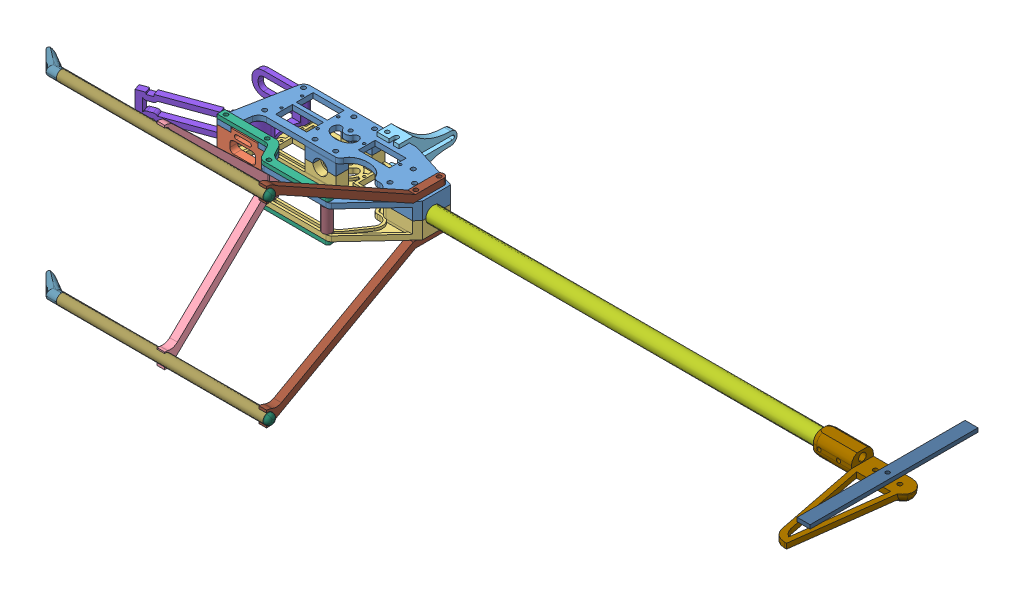
SolidWorks assembly helicopter_v5_assembly, configuration По умолчанию. Lengths in mm.
Overall size (563.49 164 196.13).
20 component instances, 15 part files, 49 mates.
Components (placement in the parent):
- frame_v5_half_left-1: frame_v5_half_left [По умолчанию] at (57.718 86.6344 66.9188) size (134.96 13 71.7)
- motor_frame-1: motor_frame [По умолчанию] at (18.368 77.6344 100.9188) x (1 0 0) z (0 -1 0) size (40 6 24)
- frame_v5_half_right-1: frame_v5_half_right [По умолчанию] at (57.718 64.6344 66.9188) size (134.96 13 71.7)
- chassis_v5-1: chassis_v5 [Default] at (45.218 77.6344 120.8231) x (0 -1 0) z (0 0 1) size (164 7 87.2)
- swash_rail-1: swash_rail [По умолчанию] at (83.718 77.5344 52.9188) x (1 0 0) z (0 1 0) size (18.35 45 34.51)
- lower_frame_v5-1: lower_frame_v5 [По умолчанию] at (57.718 90.6344 66.9188) size (99.55 3 19.7)
- lower_frame_v5-2: lower_frame_v5 [По умолчанию] at (57.718 61.6344 66.9188) size (99.55 3 19.7)
- tail_boom-1: tail_boom [Default] at (112.8303 77.6344 74.3035) x (0 0.376859 -0.92627) z (0 -0.92627 -0.376859) size (12 347 12)
- battery_mount-1: battery_mount [Default] at (14.718 86.6344 88.9188) x (-1 0 0) z (0 0 1) size (73.78 18 66.23)
- tail_motor_mount-1: tail_motor_mount [По умолчанию] at (453.8954 79.938 65.8035) x (1 0 0) z (0 -1 0) size (69.62 97.35 16.58)
- tail_prop_model-1: tail_prop_model [Default] at (484.3303 77.1344 74.3035) size (10 3 130)
- chassis_rear_v5-1: chassis_rear_v5 [Default] at (124.718 89.6344 86.1188) x (0 -1 0) z (0 0 1) size (68 6 140.23)
- chassis_rear_v5-2: chassis_rear_v5 [Default] at (130.718 65.6344 86.1188) x (0 1 0) z (0 0 1) size (68 6 140.23)
- carbon_skid-1: carbon_skid [Default] at (-29.282 2.6344 200.2088) x (0 -1 0) z (0 0 1) size (8 160 8)
- carbon_skid-2: carbon_skid [Default] at (130.718 152.6344 200.2088) x (0 1 0) z (0 0 1) size (8 160 8)
- frame_spacer-1: frame_spacer [Default] at (93.718 68.6344 117.6231) size (7 18 7)
- chassis_v3_skid_cap_front-1: chassis_v3_skid_cap_front [По умолчанию] at (-46.4523 148.6344 199.9451) size (31 8 15)
- chassis_v3_skid_cap_front-2: chassis_v3_skid_cap_front [По умолчанию] at (-46.4523 -1.3656 199.9451) size (31 8 15)
- chassis_v3_skid_cap_rear-3: chassis_v3_skid_cap_rear [По умолчанию] at (147.8884 151.3508 204.0065) x (-1 0 0) z (0 -0.924225 -0.381849) size (11.5 8 8)
- chassis_v3_skid_cap_rear-4: chassis_v3_skid_cap_rear [По умолчанию] at (147.8884 1.3508 204.0065) x (-1 0 0) z (0 -0.924225 -0.381849) size (11.5 8 8)
Mates (geometry in assembly coordinates):
- Концентричный1: concentric anti-aligned: cylinder of frame_v5_half_left-1 through (1.718 90.6344 103.9188) axis (0 -1 0) radius 1.7; cylinder of motor_frame-1 through (1.718 65.6344 103.9188) axis (0 1 0) radius 1.6
- Совпадение1: coincident anti-aligned: plane of frame_v5_half_left-1 through (47.9182 86.6344 115.6231) normal (0 -1 0); plane of motor_frame-1 through (8.718 86.6344 106.9188) normal (0 1 0)
- Концентричный2: concentric anti-aligned: cylinder of frame_v5_half_left-1 through (33.718 90.6344 103.9188) axis (0 -1 0) radius 1.7; cylinder of motor_frame-1 through (33.718 65.6344 103.9188) axis (0 1 0) radius 1.6
- Концентричный3: concentric anti-aligned: cylinder of motor_frame-1 through (1.718 65.6344 103.9188) axis (0 1 0) radius 1.6; cylinder of frame_v5_half_right-1 through (1.718 68.6344 103.9188) axis (0 -1 0) radius 1.7
- Концентричный4: concentric anti-aligned: cylinder of motor_frame-1 through (33.718 65.6344 103.9188) axis (0 1 0) radius 1.6; cylinder of frame_v5_half_right-1 through (33.718 68.6344 103.9188) axis (0 -1 0) radius 1.7
- Совпадение2: coincident anti-aligned: plane of motor_frame-1 through (-2.132 68.6344 106.9188) normal (0 -1 0); plane of frame_v5_half_right-1 through (47.9182 68.6344 115.6231) normal (0 1 0)
- Concentric1: concentric anti-aligned: cylinder of frame_v5_half_left-1 through (48.718 90.6344 117.6231) axis (0 -1 0) radius 1.7; cylinder of chassis_v5-1 through (48.718 -4.3656 117.6231) axis (0 1 0) radius 1.75
- Coincident1: coincident anti-aligned: plane of frame_v5_half_left-1 through (47.9182 86.6344 115.6231) normal (0 -1 0); plane of chassis_v5-1 through (52.218 86.6344 113.6231) normal (0 1 0)
- Parallel3: parallel aligned: plane of frame_v5_half_right-1 through (53.4322 68.6344 114.6206) normal (0 0 -1); plane of chassis_v5-1 through (52.218 86.6344 113.6231) normal (0 0 -1)
- Concentric3: concentric anti-aligned: cylinder of frame_v5_half_left-1 through (75.718 90.6344 52.9188) axis (0 -1 0) radius 1.7; cylinder of swash_rail-1 through (75.718 61.5334 52.9188) axis (0 1 0) radius 1.6
- Coincident6: coincident anti-aligned: plane of frame_v5_half_left-1 through (94.3308 90.6344 48.9188) normal (0 0 -1); plane of swash_rail-1 through (83.718 77.5344 48.9188) normal (0 0 1)
- Coincident7: coincident anti-aligned: plane of frame_v5_half_left-1 through (47.9182 90.6344 115.6231) normal (0 1 0); plane of swash_rail-1 through (88.718 90.6344 56.9188) normal (0 -1 0)
- Concentric4: concentric aligned: cylinder of frame_v5_half_left-1 through (1.718 90.6344 103.9188) axis (0 -1 0) radius 1.7; cylinder of lower_frame_v5-1 through (1.718 93.6344 103.9188) axis (0 -1 0) radius 1.6
- Concentric5: concentric aligned: cylinder of frame_v5_half_left-1 through (93.718 90.6344 117.6231) axis (0 -1 0) radius 1.7; cylinder of lower_frame_v5-1 through (93.718 93.6344 117.6231) axis (0 -1 0) radius 1.6
- Coincident8: coincident anti-aligned: plane of frame_v5_half_left-1 through (47.9182 90.6344 115.6231) normal (0 1 0); plane of lower_frame_v5-1 through (47.9182 90.6344 115.6231) normal (0 -1 0)
- Concentric6: concentric aligned: cylinder of frame_v5_half_right-1 through (1.718 68.6344 103.9188) axis (0 -1 0) radius 1.7; cylinder of lower_frame_v5-2 through (1.718 64.6344 103.9188) axis (0 -1 0) radius 1.6
- Concentric7: concentric aligned: cylinder of frame_v5_half_right-1 through (93.718 68.6344 117.6231) axis (0 -1 0) radius 1.7; cylinder of lower_frame_v5-2 through (93.718 64.6344 117.6231) axis (0 -1 0) radius 1.6
- Coincident9: coincident anti-aligned: plane of frame_v5_half_right-1 through (47.9182 64.6344 115.6231) normal (0 -1 0); plane of lower_frame_v5-2 through (47.9182 64.6344 115.6231) normal (0 1 0)
- Concentric8: concentric anti-aligned: cylinder of frame_v5_half_right-1 through (112.8303 77.6344 74.3035) axis (1 0 0) radius 6; cylinder of tail_boom-1 through (459.8303 77.6344 74.3035) axis (-1 0 0) radius 6
- Coincident10: coincident anti-aligned: plane of frame_v5_half_left-1 through (112.8303 77.6344 74.3035) normal (1 0 0); plane of tail_boom-1 through (112.8303 77.6344 74.3035) normal (-1 0 0)
- Concentric9: concentric anti-aligned: cylinder of frame_v5_half_left-1 through (10.718 90.6344 52.9188) axis (0 -1 0) radius 1.7; cylinder of battery_mount-1 through (10.718 68.6344 52.9188) axis (0 1 0) radius 1.75
- Coincident11: coincident anti-aligned: plane of frame_v5_half_left-1 through (47.9182 86.6344 115.6231) normal (0 -1 0); plane of battery_mount-1 through (14.718 86.6344 88.9188) normal (0 1 0)
- Concentric10: concentric anti-aligned: cylinder of frame_v5_half_right-1 through (10.718 68.6344 82.9188) axis (0 -1 0) radius 1.7; cylinder of battery_mount-1 through (10.718 68.6344 82.9188) axis (0 1 0) radius 1.75
- Concentric11: concentric aligned: cylinder of tail_boom-1 through (459.8303 77.6344 74.3035) axis (-1 0 0) radius 6; cylinder of tail_motor_mount-1 through (459.8303 77.6344 74.3035) axis (-1 0 0) radius 6.15
- Parallel4: parallel aligned: plane of frame_v5_half_left-1 through (47.9182 90.6344 115.6231) normal (0 1 0); plane of tail_motor_mount-1 through (266.872 85.6344 70.2054) normal (0 1 0)
- Coincident13: coincident anti-aligned: plane of tail_boom-1 through (459.8303 77.6344 74.3035) normal (1 0 0); plane of tail_motor_mount-1 through (459.8303 77.6344 74.3035) normal (-1 0 0)
- Coincident14: coincident anti-aligned: plane of tail_motor_mount-1 through (504.8303 77.1344 82.8035) normal (0 1 0); plane of tail_prop_model-1 through (484.3303 77.1344 74.3035) normal (0 -1 0)
- Concentric12: concentric aligned: circle of frame_v5_half_left-1; cylinder of chassis_rear_v5-1 through (127.718 89.6344 64.9188) axis (0 1 0) radius 1.65
- Concentric13: concentric aligned: circle of frame_v5_half_left-1; circle of chassis_rear_v5-1
- Concentric14: concentric aligned: cylinder of frame_v5_half_right-1 through (127.718 68.6344 64.9188) axis (0 -1 0) radius 1.7; cylinder of chassis_rear_v5-2 through (127.718 65.6344 64.9188) axis (0 -1 0) radius 1.65
- Concentric15: concentric aligned: cylinder of frame_v5_half_right-1 through (127.718 68.6344 82.9188) axis (0 -1 0) radius 1.7; cylinder of chassis_rear_v5-2 through (127.718 65.6344 82.9188) axis (0 -1 0) radius 1.65
- Coincident18: coincident anti-aligned: plane of frame_v5_half_left-1 through (47.9182 90.6344 115.6231) normal (0 1 0); plane of chassis_rear_v5-1 through (127.2784 90.6344 75.5945) normal (0 -1 0)
- Coincident19: coincident anti-aligned: plane of frame_v5_half_right-1 through (47.9182 64.6344 115.6231) normal (0 -1 0); plane of chassis_rear_v5-2 through (128.1577 64.6344 75.5945) normal (0 1 0)
- Concentric16: concentric anti-aligned: cylinder of chassis_rear_v5-1 through (130.718 152.6344 200.2088) axis (-1 0 0) radius 4.1; cylinder of carbon_skid-2 through (-29.282 152.6344 200.2088) axis (1 0 0) radius 4
- Coincident20: coincident aligned: plane of chassis_rear_v5-1 through (130.718 89.6344 86.1188) normal (1 0 0); plane of carbon_skid-2 through (130.718 152.6344 200.2088) normal (1 0 0)
- Concentric17: concentric anti-aligned: cylinder of chassis_rear_v5-2 through (124.718 2.6344 200.2088) axis (1 0 0) radius 4.1; cylinder of carbon_skid-1 through (130.718 2.6344 200.2088) axis (-1 0 0) radius 4
- Coincident21: coincident aligned: plane of chassis_rear_v5-2 through (130.718 65.6344 86.1188) normal (1 0 0); plane of carbon_skid-1 through (130.718 2.6344 200.2088) normal (1 0 0)
- Concentric18: concentric aligned: cylinder of lower_frame_v5-1 through (93.718 93.6344 117.6231) axis (0 -1 0) radius 1.6; cylinder of frame_spacer-1 through (93.718 86.6344 117.6231) axis (0 -1 0) radius 3.5
- Coincident22: coincident anti-aligned: plane of frame_v5_half_left-1 through (47.9182 86.6344 115.6231) normal (0 -1 0); plane of frame_spacer-1 through (93.718 86.6344 117.6231) normal (0 1 0)
- Concentric19: concentric anti-aligned: cylinder of carbon_skid-2 through (-29.282 152.6344 200.2088) axis (1 0 0) radius 3; cylinder of chassis_v3_skid_cap_front-1 through (-21.282 152.6344 200.2088) axis (-1 0 0) radius 2.8
- Concentric20: concentric aligned: cylinder of carbon_skid-1 through (130.718 2.6344 200.2088) axis (-1 0 0) radius 3; cylinder of chassis_v3_skid_cap_front-2 through (-21.282 2.6344 200.2088) axis (-1 0 0) radius 2.8
- Coincident23: coincident anti-aligned: plane of carbon_skid-2 through (-29.282 152.6344 200.2088) normal (-1 0 0); plane of chassis_v3_skid_cap_front-1 through (-29.282 156.6344 196.2088) normal (1 0 0)
- Coincident24: coincident anti-aligned: plane of carbon_skid-1 through (-29.282 2.6344 200.2088) normal (-1 0 0); plane of chassis_v3_skid_cap_front-2 through (-29.282 6.6344 196.2088) normal (1 0 0)
- Parallel5: parallel aligned: plane of chassis_v3_skid_cap_front-1 through (-52.282 156.6344 189.2088) normal (0 0 -1); plane of chassis_v3_skid_cap_front-2 through (-52.282 6.6344 189.2088) normal (0 0 -1)
- Coincident26: coincident: point of tail_motor_mount-1; point of tail_prop_model-1
- Concentric21: concentric anti-aligned: cylinder of carbon_skid-1 through (130.718 2.6344 200.2088) axis (-1 0 0) radius 3; cylinder of chassis_v3_skid_cap_rear-4 through (122.718 2.6344 200.2088) axis (1 0 0) radius 2.8
- Concentric22: concentric aligned: cylinder of carbon_skid-2 through (-29.282 152.6344 200.2088) axis (1 0 0) radius 3; cylinder of chassis_v3_skid_cap_rear-3 through (122.718 152.6344 200.2088) axis (1 0 0) radius 2.8
- Coincident27: coincident aligned: circle of carbon_skid-2; plane of chassis_v3_skid_cap_rear-3 through (130.718 157.8587 198.0393) normal (-1 0 0)
- Coincident28: coincident anti-aligned: plane of carbon_skid-1 through (130.718 2.6344 200.2088) normal (1 0 0); plane of chassis_v3_skid_cap_rear-4 through (130.718 7.8587 198.0393) normal (-1 0 0)
